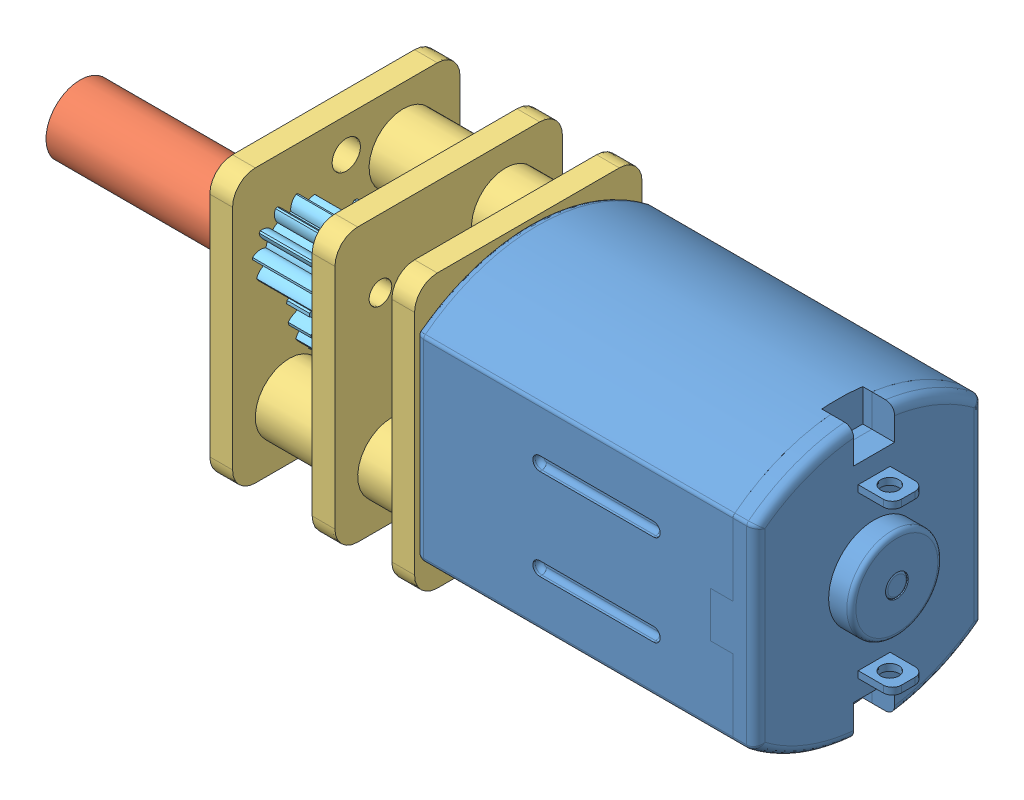
SolidWorks assembly n20 motor, configuration 轴长10mm. Lengths in mm.
Overall size (36.2 12.14 10.87).
11 component instances, 5 part files, 21 mates.
Components (placement in the parent):
- motor-1: motor [默认] at (-3.4114 0.0905 -5.0483)
- n20_shaft-1: n20_shaft [10mm] at (-13.1114 0.0905 -0.0483) x (0 -0.096252 -0.995357) z (0 0.995357 -0.096252) size (3 12 3)
- n20_gearbox-1: n20_gearbox [默认] at (-11.4114 0.0905 -0.0483) x (0 1 0) z (-1 0 0)
- cross recessed countersunk head screws gb1-1: cross recessed countersunk head screws gb1 [GB_CROSS_SCREWS_TYPE4 M1.6X3-2  H type-N] at (-12.4614 -3.4095 2.4517)
- cross recessed countersunk head screws gb1-2: cross recessed countersunk head screws gb1 [GB_CROSS_SCREWS_TYPE4 M1.6X3-2  H type-N] at (-12.4614 3.5905 -2.5483) x (1 0 0) z (0 0.116872 0.993147)
- spur gear_gb-1: spur gear_gb [GB - Spur gear 0.25M 10T 20PA 2FW ---S10A75H50L1.0N] at (-8.4114 -2.9095 -2.5483) x (1 0 0) z (0 -0.845955 0.533254)
- spur gear_gb-2: spur gear_gb [GB - Spur gear 0.25M 10T 20PA 2FW ---S10A75H50L1.0N] at (-4.4114 0.0905 -0.0483) x (-1 0 0) z (0 0.404067 -0.914729)
- spur gear_gb-4: spur gear_gb [GB - Spur gear 0.25M 16T 20PA 2FW ---S16A75H50L1.0N] at (-6.4114 -2.9095 -2.5483) x (1 0 0) z (0 -0.712706 0.701463)
- spur gear_gb-6: spur gear_gb [GB - Spur gear 0.25M 19T 20PA 2FW ---S19A75H50L1.0N] at (-9.9114 0.0905 -0.0483) x (1 0 0) z (0 0.321468 -0.94692)
- spur gear_gb-8: spur gear_gb [GB - Spur gear 0.25M 11T 20PA 3FW ---S11A75H50L1.0N] at (-10.9114 3.0905 2.9517) x (1 0 0) z (0 -0.604063 0.796937)
- spur gear_gb-10: spur gear_gb [GB - Spur gear 0.25M 19T 20PA 1FW ---S19A75H50L1.0N] at (-11.4114 0.0905 -0.0483) x (1 0 0) z (0 -0.330889 0.94367)
Mates (geometry in assembly coordinates):
- 同心1: concentric anti-aligned: cylinder of motor-1 through (-6.4114 0.0905 -0.0483) axis (1 0 0) radius 1; cylinder of n20_gearbox-1 through (-3.4114 0.0905 -0.0483) axis (-1 0 0) radius 0.5329
- 重合1: coincident anti-aligned: plane of motor-1 through (-3.4114 -5.9095 4.9517) normal (-1 0 0); plane of n20_gearbox-1 through (-3.4114 0.0905 -0.0483) normal (1 0 0)
- 重合2: coincident aligned: plane of motor-1 through (-3.4114 0.0905 4.9517) normal (0 0 1); plane of n20_gearbox-1 through (-3.4114 6.0905 4.9517) normal (0 0 1)
- 同心2: concentric aligned: cylinder of n20_shaft-1 through (-23.1114 0.0905 -0.0483) axis (1 0 0) radius 1.5; cylinder of n20_gearbox-1 through (-12.4114 0.0905 -0.0483) axis (1 0 0) radius 1.5
- 同心3: concentric anti-aligned: cone of n20_gearbox-1 through (-7.9114 3.5905 -2.5483) axis (-1 0 0); cylinder of cross recessed countersunk head screws gb1-2 through (-11.4614 3.5905 -2.5483) axis (1 0 0) radius 785.3982
- 重合4: coincident aligned: cone of n20_gearbox-1 through (-12.4114 3.5905 -2.5483) axis (1 0 0); cone of cross recessed countersunk head screws gb1-2 through (-11.4614 3.5905 -2.5483) axis (1 0 0)
- 同心8: concentric anti-aligned: cylinder of n20_gearbox-1 through (-7.9114 -3.4095 2.4517) axis (-1 0 0) radius 0.9; cylinder of cross recessed countersunk head screws gb1-1 through (-7.9456 -3.4095 2.4517) axis (1 0 0) radius 0.8
- 重合5: coincident aligned: cone of n20_gearbox-1 through (-12.4114 -3.4095 2.4517) axis (1 0 0); cone of cross recessed countersunk head screws gb1-1 through (-11.4614 -3.4095 2.4517) axis (1 0 0)
- 同心10: concentric aligned: cylinder of motor-1 through (-6.4114 0.0905 -0.0483) axis (1 0 0) radius 1; cylinder of spur gear_gb-2 through (-54.4115 0.0905 -0.0483) axis (1 0 0) radius 0.5
- 同心11: concentric aligned: cylinder of n20_gearbox-1 through (-3.4114 -2.9095 -2.5483) axis (-1 0 0) radius 0.5; cylinder of spur gear_gb-4 through (43.5886 -2.9095 -2.5483) axis (-1 0 0) radius 0.5
- 重合6: coincident anti-aligned: plane of n20_gearbox-1 through (-4.4114 0.0905 -0.0483) normal (-1 0 0); plane of spur gear_gb-4 through (-4.4114 -2.9095 -2.5483) normal (1 0 0)
- 同心12: concentric aligned: cylinder of n20_gearbox-1 through (-6.9114 0.0905 -0.0483) axis (-1 0 0) radius 0.5; cylinder of spur gear_gb-6 through (40.0886 0.0905 -0.0483) axis (-1 0 0) radius 0.5
- 重合7: coincident anti-aligned: plane of n20_gearbox-1 through (-7.9114 0.0905 -0.0483) normal (-1 0 0); plane of spur gear_gb-6 through (-7.9114 0.0905 -0.0483) normal (1 0 0)
- 同心13: concentric aligned: cylinder of spur gear_gb-1 through (41.5886 -2.9095 -2.5483) axis (-1 0 0) radius 0.5; cylinder of spur gear_gb-4 through (43.5886 -2.9095 -2.5483) axis (-1 0 0) radius 0.5
- 重合8: coincident anti-aligned: plane of spur gear_gb-1 through (-6.4114 -2.9095 -2.5483) normal (1 0 0); plane of spur gear_gb-4 through (-6.4114 -2.9095 -2.5483) normal (-1 0 0)
- 同心14: concentric aligned: cylinder of n20_gearbox-1 through (-6.9114 3.0905 2.9517) axis (-1 0 0) radius 0.5; cylinder of spur gear_gb-8 through (39.0886 3.0905 2.9517) axis (-1 0 0) radius 0.5
- 同心15: concentric aligned: cylinder of spur gear_gb-6 through (40.0886 0.0905 -0.0483) axis (-1 0 0) radius 0.5; cylinder of spur gear_gb-10 through (38.5886 0.0905 -0.0483) axis (-1 0 0) radius 0.5
- 重合9: coincident anti-aligned: plane of n20_gearbox-1 through (-7.9114 0.0905 -0.0483) normal (-1 0 0); plane of spur gear_gb-8 through (-7.9114 3.0905 2.9517) normal (1 0 0)
- 重合10: coincident anti-aligned: plane of n20_gearbox-1 through (-11.4114 0.0905 -0.0483) normal (1 0 0); plane of spur gear_gb-10 through (-11.4114 0.0905 -0.0483) normal (-1 0 0)
- 重合11: coincident anti-aligned: plane of n20_gearbox-1 through (-4.4114 0.0905 -0.0483) normal (-1 0 0); plane of spur gear_gb-2 through (-4.4114 0.0905 -0.0483) normal (1 0 0)
- Coincident2: coincident aligned: plane of n20_shaft-1 through (-13.1114 0.0905 -0.0483) normal (-1 0 0); plane of n20_gearbox-1 through (-13.1114 0.0905 -0.0483) normal (-1 0 0)
